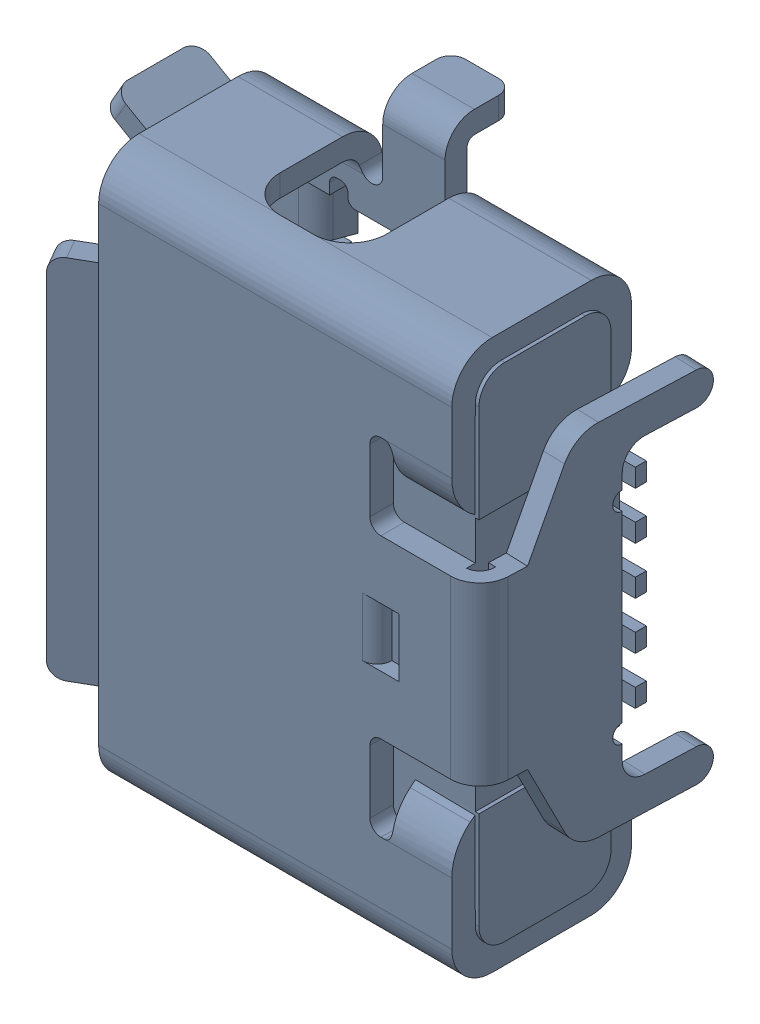
SolidWorks assembly J1, configuration Standard. Lengths in mm.
Overall size (5.9 8.66 3.36).
2 component instances, 1 part files, 0 mates.
Components (placement in the parent):
- 475900001-1: 475900001 [Standard] at (-26.2999 1.3001 0.26) x (0 1 0) z (1 0 0) size (8.66 3.36 5.9)
  - Open CASCADE STEP translator 6.8 1.11.1.1-1: Open CASCADE STEP translator 6.8 1.11.1.1 [Standard] at origin size (8.66 3.36 5.9)
